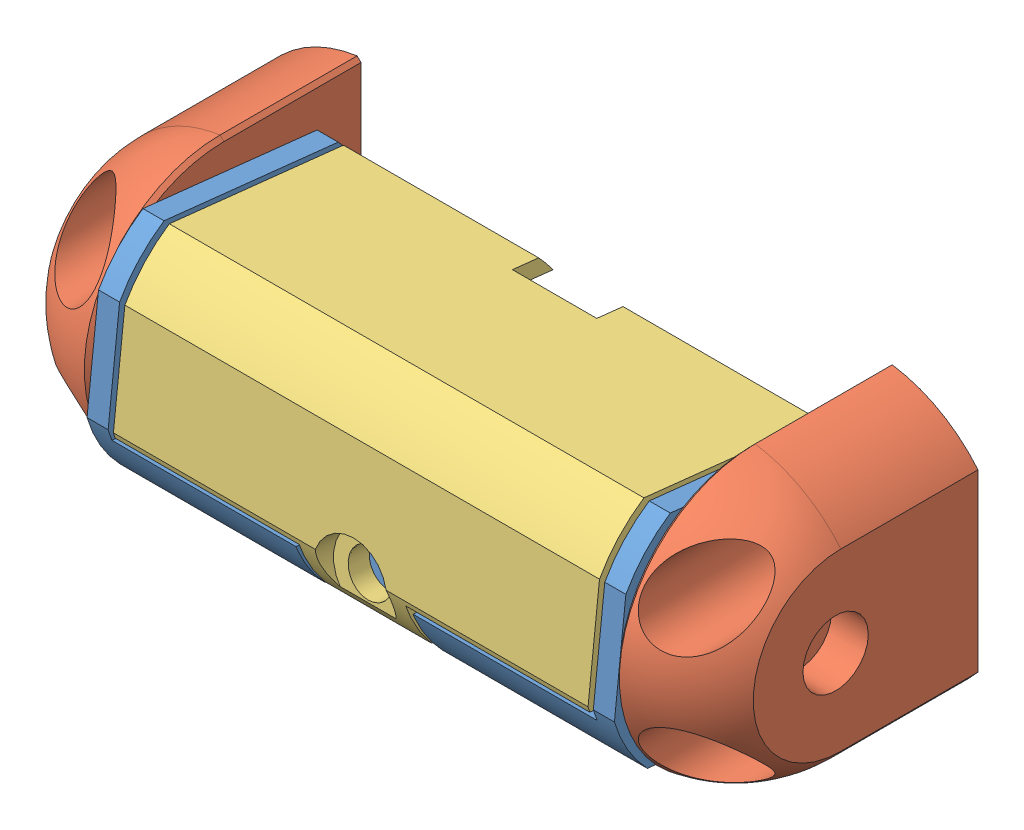
SolidWorks assembly 1_sonar_support_assembly, configuration Valor predeterminado. Lengths in mm.
Overall size (67 25.73 26.78).
4 component instances, 3 part files, 8 mates.
Components (placement in the parent):
- sonar-case-1: sonar-case [Valor predeterminado] at (-27.1976 2.3826 144.5919) x (1 0 0) z (0 0.994096 -0.108507) size (50 24 20.22)
- sonar-support-1: sonar-support [Valor predeterminado] at (-27.1976 -48.7862 91.6121) size (8.5 25.73 25.87)
- sonar-support-2: sonar-support [Valor predeterminado] at (-27.1976 62.2138 91.6121) x (-1 0 0) z (0 0 1) size (8.5 25.73 25.87)
- sonar-lid-1: sonar-lid [Valor predeterminado] at (-27.1976 -8.837 41.8024) x (-1 0 0) z (0 -0.994096 0.108507) size (45 22.16 19.5)
Mates (geometry in assembly coordinates):
- Concêntrico2: concentric aligned: circle of sonar-case-1; circle of sonar-support-1
- Concêntrico3: concentric anti-aligned: circle of sonar-support-1; circle of sonar-support-2
- Coincidente8: coincident anti-aligned: plane of sonar-case-1 through (-52.1976 15.3526 79.0979) normal (-1 0 0); plane of sonar-support-1 through (-52.1976 19.2138 104.4775) normal (1 0 0)
- Coincidente9: coincident anti-aligned: plane of sonar-case-1 through (-2.1976 15.3526 79.0979) normal (1 0 0); plane of sonar-support-2 through (-2.1976 -5.7862 104.4775) normal (-1 0 0)
- Paralelo2: parallel anti-aligned: plane of sonar-case-1 through (-27.1976 1.563 100.2188) normal (0 0.108507 0.994096); plane of sonar-lid-1 through (-27.1976 -2.3591 101.1499) normal (0 -0.108507 -0.994096)
- Paralelo3: parallel aligned: plane of sonar-case-1 through (-32.7476 2.0513 104.6923) normal (1 0 0); plane of sonar-lid-1 through (-22.1476 6.0037 104.0388) normal (1 0 0)
- Concêntrico4: concentric anti-aligned: circle of sonar-case-1; circle of sonar-lid-1
- Concêntrico7: concentric anti-aligned: circle of sonar-case-1; circle of sonar-lid-1
